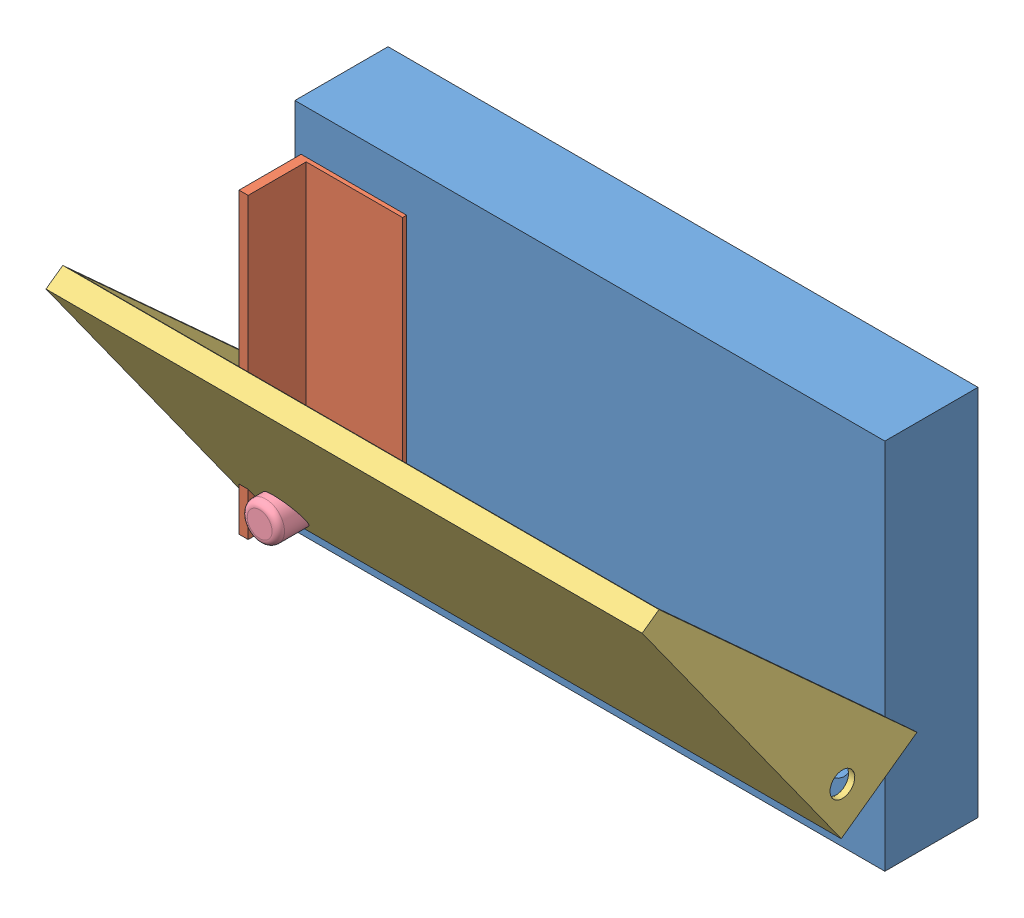
SolidWorks assembly Ensamblaje1, configuration Predeterminado. Lengths in mm.
Overall size (102 61.99 54.58).
6 component instances, 6 part files, 10 mates.
Components (placement in the parent):
- Pieza3-1: Pieza3 [Predeterminado] at (-2.0667 -4.2129 90.5) size (95 60 15)
- Pieza2-3: Pieza2 [Predeterminado] at (-40.0667 -5.2129 115.5) x (0 -1 0) z (0 0 -1) size (58.24 34.03 10)
- Pieza2 - izq-1: Pieza2 - izq [Predeterminado] at (35.9333 -5.2129 115.5) x (0 1 0) z (0 0 -1) size (58.24 34.03 10) (hidden)
- PiezaArriba-3: PiezaArriba [Predeterminado] at (-2.0667 -3.3136 129.0474) x (-1 0 0) z (0 0.58294 -0.812515) size (96 55 15)
- Pieza larga-1: Pieza larga [Predeterminado] at (-52.0667 -23.8152 110.518) x (0 0 1) z (1 0 0) size (14.38 96.1 14.38) (hidden)
- Pieza4-5: Pieza4 [Predeterminado] at (-40.0667 -20.9637 120.6736) x (-0.595829 -0.803111 0) z (0 0 -1) size (6 6 20)
Mates (geometry in assembly coordinates):
- Distancia8: distance = 1 mm: plane of Pieza3-1 through (-49.5667 25.7871 105.5) normal (-1 0 0); plane of Pieza2-3 through (-48.5667 18.7871 105.5) normal (-1 0 0)
- Distancia5: distance = 1 mm: plane of Pieza3-1 through (45.4333 25.7871 105.5) normal (1 0 0); plane of Pieza2 - izq-1 through (44.4333 -29.2129 105.5) normal (1 0 0)
- Coincidente14: coincident: plane of Pieza3-1 through (-2.0667 -4.2129 105.5) normal (0 0 1); plane of Pieza2 - izq-1 through (35.9333 -5.2129 105.5) normal (0 0 -1)
- Distancia3: distance = 5 mm: plane of Pieza2 - izq-1 through (44.4333 -29.2129 105.5) normal (0 -1 0); plane of Pieza3-1 through (-49.5667 -34.2129 105.5) normal (0 -1 0)
- Distancia4: distance = 5 mm: plane of Pieza2-3 through (-48.5667 -29.2129 105.5) normal (0 -1 0); plane of Pieza3-1 through (-49.5667 -34.2129 105.5) normal (0 -1 0)
- Coincidente18: coincident: plane of Pieza3-1 through (-2.0667 -4.2129 105.5) normal (0 0 1); plane of Pieza2-3 through (-40.0667 -5.2129 105.5) normal (0 0 -1)
- Distancia9: distance = 0.5 mm: plane of Pieza2-3 through (-48.5667 18.7871 105.5) normal (-1 0 0); plane of PiezaArriba-3 through (-49.0667 -84.6717 203.2406) normal (1 0 0)
- Concéntrica8: concentric: cone of Pieza3-1 through (-40.0667 -20.9637 105.5) axis (0 0 -1); cylinder of Pieza4-5 through (-40.0667 -20.9637 100.6736) axis (0 0 1) radius 3
- Distancia límite3: limit distance = 15.1736 mm: plane of Pieza4-5 through (-40.0667 -20.9637 120.6736) normal (0 0 1); plane of Pieza3-1 through (-2.0667 -4.2129 105.5) normal (0 0 1)
- Tangente17: tangent: cylinder of Pieza2-3 through (-47.0909 -20.8457 110.6907) axis (1 0 0) radius 1.45; circle of PiezaArriba-3
